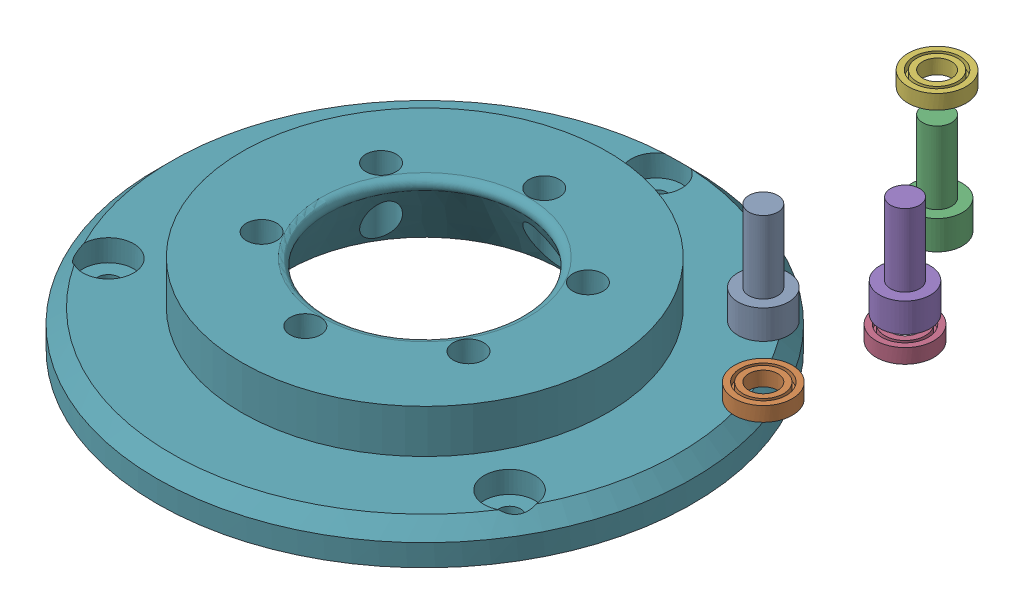
SolidWorks assembly OutputShaftAssem_2, configuration Default. Lengths in mm.
Overall size (91.75 41.91 77.34).
7 component instances, 3 part files, 13 mates.
Components (placement in the parent):
- M4_10mm-1: M4_10mm [Default] at (47.9015 22.9105 1.137) size (7 14 7)
- 4x8x3_bearing_uxcell-1: 4x8x3_bearing_uxcell [Default] at (47.9015 12.5896 1.137) size (8 2 8)
- M4_10mm-2: M4_10mm [Default] at (34.4234 8.1315 -36.3434) size (7 14 7)
- 4x8x3_bearing_uxcell-2: 4x8x3_bearing_uxcell [Default] at (50.7535 12.5896 -15.5854) size (8 2 8)
- M4_10mm-3: M4_10mm [Default] at (50.7535 16.803 -15.5854) size (7 14 7)
- 4x8x3_bearing_uxcell-3: 4x8x3_bearing_uxcell [Default] at (34.4234 24.4426 -36.3434) size (8 2 8)
- bearing_holder_50x60x6-1: bearing_holder_50x60x6 [Default] at origin size (74 11 74)
Mates (geometry in assembly coordinates):
- Coincident1: coincident anti-aligned: plane of OutputShaftBottom_2-1 through (12.545 11.0896 35.6173) normal (0 -1 0); plane of M4_10mm-1 through (47.9015 26.9105 1.137) normal (0 1 0)
- Concentric1: concentric anti-aligned: cylinder of OutputShaftBottom_2-1 through (12.545 7.0896 35.6173) axis (0 1 0) radius 2; cylinder of M4_10mm-1 through (47.9015 36.9105 1.137) axis (0 -1 0) radius 2
- Concentric2: concentric aligned: cylinder of M4_10mm-1 through (47.9015 36.9105 1.137) axis (0 -1 0) radius 2; cylinder of 4x8x3_bearing_uxcell-1 through (47.9015 15.5896 1.137) axis (0 -1 0) radius 2
- Coincident2: coincident anti-aligned: plane of OutputShaftBottom_2-1 through (12.545 13.5896 19.1173) normal (0 1 0); plane of 4x8x3_bearing_uxcell-1 through (47.9015 13.5896 1.137) normal (0 -1 0)
- Concentric3: concentric anti-aligned: cylinder of OutputShaftBottom_2-1 through (26.8344 7.0896 10.8673) axis (0 1 0) radius 2; cylinder of M4_10mm-3 through (50.7535 30.803 -15.5854) axis (0 -1 0) radius 2
- Concentric4: concentric anti-aligned: cylinder of OutputShaftBottom_2-1 through (-1.7444 7.0896 10.8673) axis (0 1 0) radius 2; cylinder of M4_10mm-2 through (34.4234 22.1315 -36.3434) axis (0 -1 0) radius 2
- Coincident3: coincident anti-aligned: plane of OutputShaftBottom_2-1 through (26.8344 11.0896 10.8673) normal (0 -1 0); plane of M4_10mm-3 through (50.7535 20.803 -15.5854) normal (0 1 0)
- Coincident4: coincident anti-aligned: plane of OutputShaftBottom_2-1 through (-1.7444 11.0896 10.8673) normal (0 -1 0); plane of M4_10mm-2 through (34.4234 12.1315 -36.3434) normal (0 1 0)
- Concentric6: concentric aligned: cylinder of 4x8x3_bearing_uxcell-2 through (50.7535 15.5896 -15.5854) axis (0 -1 0) radius 2; cylinder of M4_10mm-3 through (50.7535 30.803 -15.5854) axis (0 -1 0) radius 2
- Concentric7: concentric aligned: cylinder of M4_10mm-2 through (34.4234 22.1315 -36.3434) axis (0 -1 0) radius 2; cylinder of 4x8x3_bearing_uxcell-3 through (34.4234 27.4426 -36.3434) axis (0 -1 0) radius 2
- Coincident5: coincident anti-aligned: plane of OutputShaftBottom_2-1 through (12.545 13.5896 19.1173) normal (0 1 0); plane of 4x8x3_bearing_uxcell-2 through (50.7535 13.5896 -15.5854) normal (0 -1 0)
- Coincident6: coincident anti-aligned: plane of OutputShaftBottom_2-1 through (12.545 13.5896 19.1173) normal (0 1 0); plane of 4x8x3_bearing_uxcell-3 through (34.4234 25.4426 -36.3434) normal (0 -1 0)
- Coincident7: coordinate: point of bearing_holder_50x60x6-1
